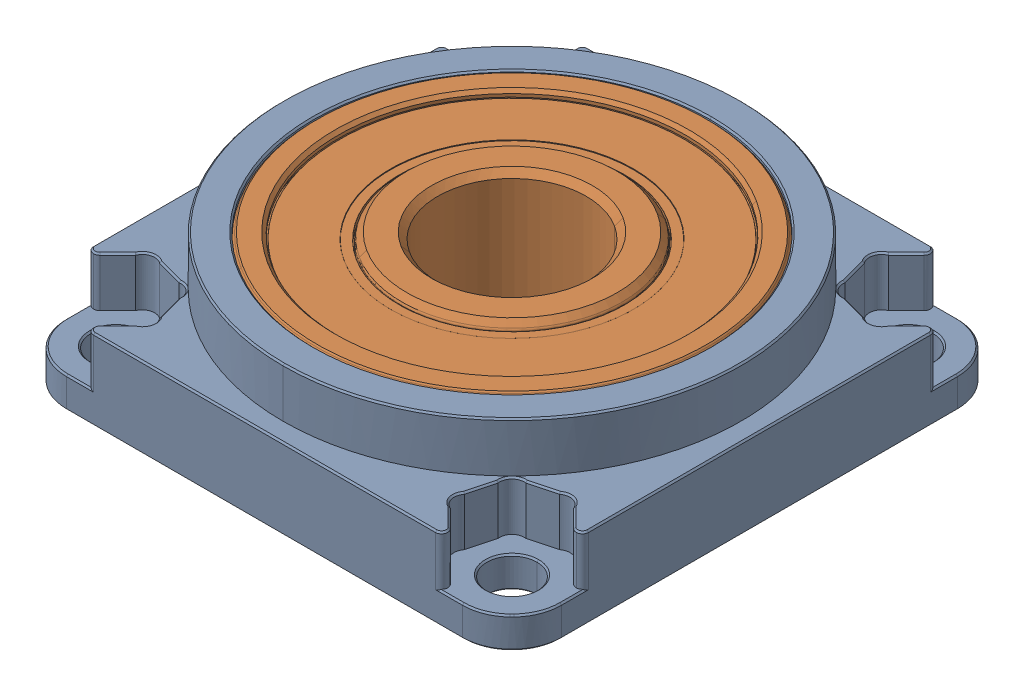
SolidWorks assembly 12mm_ID_flange_mount_pillow_block_bearing, configuration Default. Lengths in mm.
Overall size (44.21 10.5 44.21).
3 component instances, 2 part files, 0 mates.
Components (placement in the parent):
- 1622-0032-0012 assembly(2)-1: 1622-0032-0012 assembly(2) [Default] at origin size (44.21 10.5 44.21)
  - 1622-0032-0012_1-1: 1622-0032-0012_1 [Default] at (-26.5906 -3.5812 12.8977) size (40 10.5 40)
  - 1600-1032-0012_1-1: 1600-1032-0012_1 [Default] at (-26.5906 1.9188 12.8977) x (0.842116 0 0.539296) z (-0.539296 0 0.842116) size (32 10 32)
